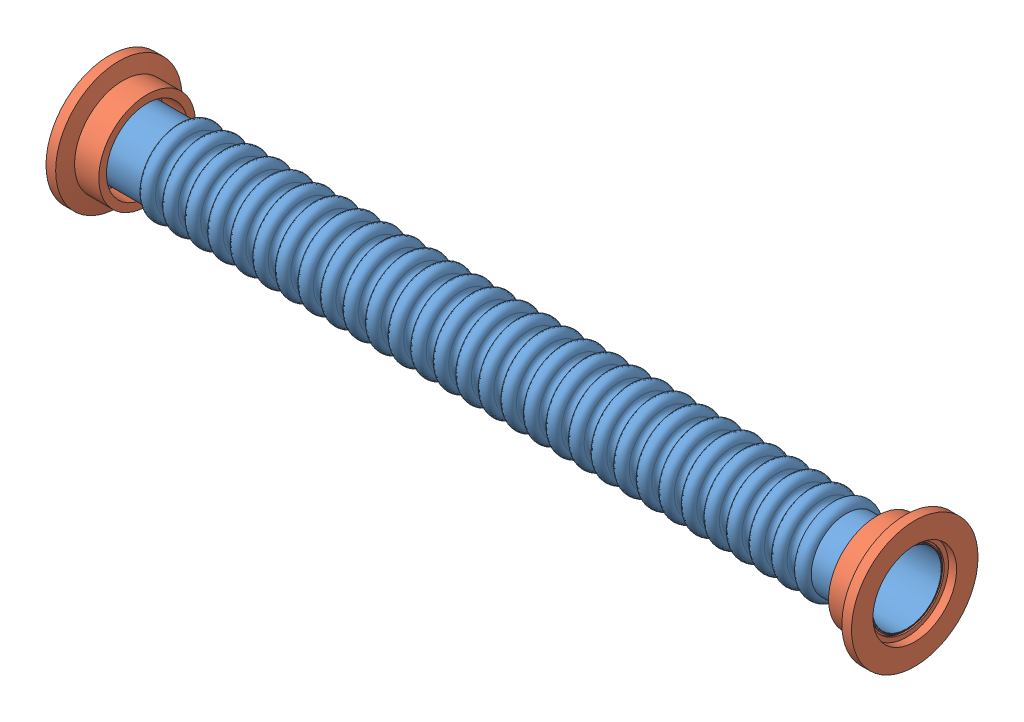
SolidWorks assembly 722021, configuration Default. Lengths in mm.
Overall size (254 52.08 52.08).
3 component instances, 2 part files, 4 mates.
Components (placement in the parent):
- 02-1: 02 [Default] at (-7.4782 44.8364 63.0085) size (248.92 26.16 26.16)
- 713002-1: 713002 [Default] at (-10.0182 44.8364 63.0085) x (0 -0.924225 -0.381849) z (1 0 0) size (39.88 39.88 11.94)
- 713002-2: 713002 [Default] at (243.9818 44.8364 63.0085) x (0 0.924225 0.381849) z (-1 0 0) size (39.88 39.88 11.94)
Mates (geometry in assembly coordinates):
- Coincident1: coincident aligned: plane of 02-1 through (241.4418 44.8364 63.0085) normal (1 0 0); plane of 713002-2 through (241.4418 44.8364 63.0085) normal (1 0 0)
- Concentric1: concentric aligned: cylinder of 02-1 through (222.3918 44.8364 63.0085) axis (1 0 0) radius 11.049; cylinder of 713002-2 through (243.9818 44.8364 63.0085) axis (1 0 0) radius 12.827
- Coincident2: coincident aligned: plane of 02-1 through (-7.4782 44.8364 63.0085) normal (-1 0 0); plane of 713002-1 through (-7.4782 44.8364 63.0085) normal (-1 0 0)
- Concentric2: concentric aligned: cylinder of 02-1 through (11.5718 44.8364 63.0085) axis (-1 0 0) radius 11.049; cylinder of 713002-1 through (-10.0182 44.8364 63.0085) axis (-1 0 0) radius 15.24
